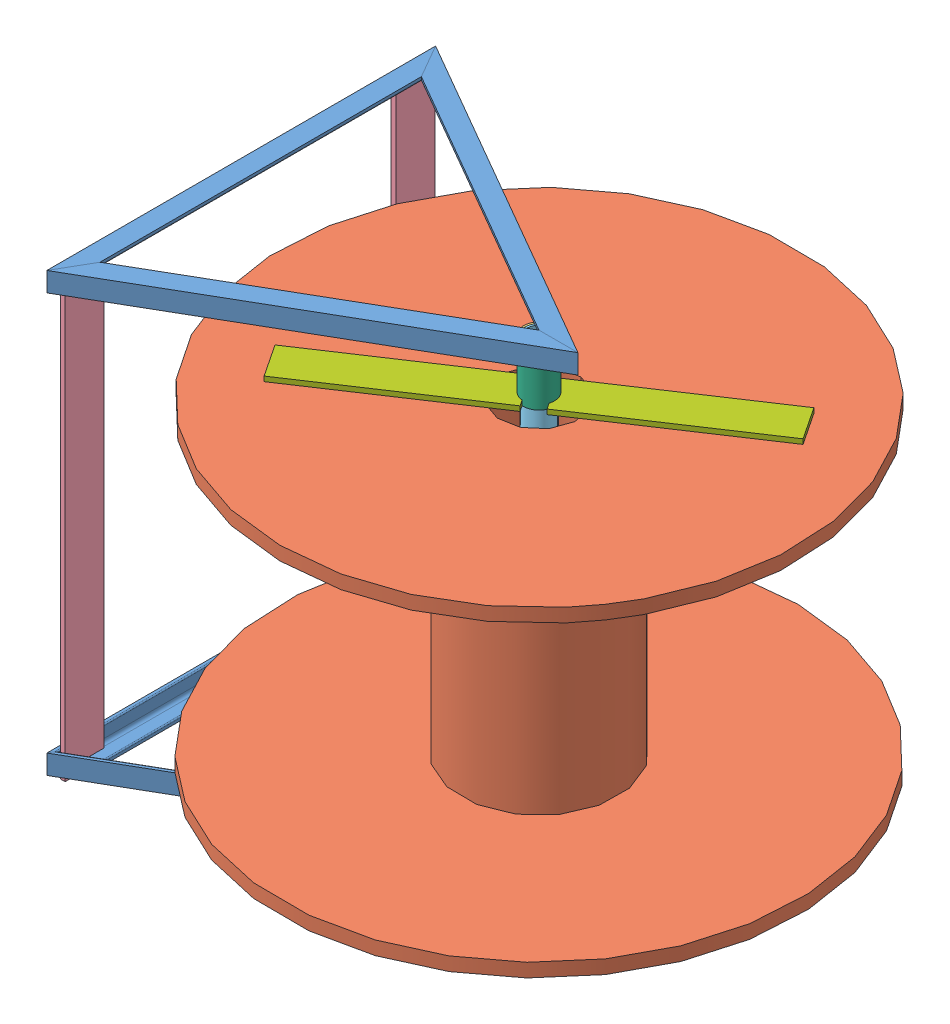
SolidWorks assembly Катушка для шланга, configuration По умолчанию. Lengths in mm.
Overall size (736.97 504 736.97).
22 component instances, 7 part files, 27 mates.
Components (placement in the parent):
- Ножка-1: Ножка [По умолчанию] at (-125.1048 -8.1589 -68.244) size (356.41 20 400)
  - Уголок-1: Уголок [По умолчанию] at (-73.7059 18.8462 -200.1369) size (20 20 400)
  - Уголок-2: Уголок [По умолчанию] at (-84.9559 18.8462 193.3679) x (-0.5 0 -0.866025) z (0.866025 0 -0.5) size (20 20 400)
  - Уголок-3: Уголок [По умолчанию] at (261.4543 18.8462 6.3583) x (-0.5 0 0.866025) z (-0.866025 0 -0.5) size (20 20 400)
- Ножка-2: Ножка [По умолчанию] at (-125.1048 464.5335 -68.5177) x (1 0 0) z (0 0 -1) size (356.41 20 400)
  - Уголок-1: Уголок [По умолчанию] at (-73.7059 18.8462 -200.1369) size (20 20 400)
  - Уголок-2: Уголок [По умолчанию] at (-84.9559 18.8462 193.3679) x (-0.5 0 -0.866025) z (0.866025 0 -0.5) size (20 20 400)
  - Уголок-3: Уголок [По умолчанию] at (261.4543 18.8462 6.3583) x (-0.5 0 0.866025) z (-0.866025 0 -0.5) size (20 20 400)
- Катушка-1: Катушка [По умолчанию] at (100.0995 379.1873 -68.3809) x (-0.824166 0 -0.566348) z (0 -1 0) size (530 530 330)
- Опора-1: Опора [По умолчанию] at (100.0995 433.1873 -68.3809) x (-0.837169 0 -0.546944) z (0 1 0) size (32 32 16)
- Опора-2: Опора [По умолчанию] at (100.0995 23.1873 -68.3809) x (-0.897984 0 -0.440028) z (0 -1 0) size (32 32 16)
- Перемычка-1: Перемычка [По умолчанию] at (-202.3106 449.1873 -258.5659) x (0 0 1) z (0 -1 0) size (40 5 452)
- Перемычка-2: Перемычка [По умолчанию] at (-202.3106 -2.8127 121.8042) x (0 0 -1) z (0 1 0) size (40 5 452)
- Вал-1: Вал [По умолчанию] at (100.0995 -50.8127 -68.3809) x (-0.495671 0 0.86851) z (0 1 0) size (28 28 500)
- Сборка - фланец-1: Сборка - фланец [По умолчанию] at (96.5514 25.4272 -65.404) x (-0.917606 0 0.397491) z (0 1 0) size (40 400 40)
  - Фланец-1: Фланец [По умолчанию] at (-4.4391 -1.3212 -2.24) size (32 32 40)
  - Деталь фланца-2: Деталь фланца [По умолчанию] at (15.5609 -201.3212 37.76) x (-1 0 0) z (0 1 0) size (40 5 190)
  - Деталь фланца-3: Деталь фланца [По умолчанию] at (-24.4391 198.6788 37.76) x (1 0 0) z (0 -1 0) size (40 5 190)
- Сборка - фланец-2: Сборка - фланец [По умолчанию] at (101.4552 430.9473 -63.9522) x (0.553322 0 0.832967) z (0 -1 0) size (40 400 40)
  - Фланец-1: Фланец [По умолчанию] at (-4.4391 -1.3212 -2.24) size (32 32 40)
  - Деталь фланца-2: Деталь фланца [По умолчанию] at (15.5609 -201.3212 37.76) x (-1 0 0) z (0 1 0) size (40 5 190)
  - Деталь фланца-3: Деталь фланца [По умолчанию] at (-24.4391 198.6788 37.76) x (1 0 0) z (0 -1 0) size (40 5 190)
Mates (geometry in assembly coordinates):
- Совпадение1: coincident anti-aligned: plane of Ножка-2/Уголок-3 through (-215.7106 449.1873 115.3379) normal (0 -1 0); plane of Опора-1 through (100.0995 449.1873 -68.3809) normal (0 1 0)
- Касательность1: tangent anti-aligned: plane of Ножка-2/Уголок-3 through (-208.3106 445.6873 128.155) normal (-0.5 0 -0.866025); cylinder of Опора-1 through (100.0995 449.1873 -68.3809) axis (0 -1 0) radius 16
- Касательность2: tangent anti-aligned: plane of Ножка-2/Уголок-2 through (138.0995 445.6873 -64.9168) normal (-0.5 0 0.866025); cylinder of Опора-1 through (100.0995 449.1873 -68.3809) axis (0 -1 0) radius 16
- Касательность3: tangent anti-aligned: plane of Ножка-1/Уголок-3 through (-208.3106 10.6873 -264.9168) normal (-0.5 0 0.866025); cylinder of Опора-2 through (100.0995 7.1873 -68.3809) axis (0 1 0) radius 16
- Совпадение2: coincident anti-aligned: plane of Ножка-1/Уголок-2 through (130.6995 7.1873 -84.6621) normal (0 1 0); plane of Опора-2 through (100.0995 7.1873 -68.3809) normal (0 -1 0)
- Касательность6: tangent anti-aligned: plane of Ножка-1/Уголок-2 through (138.0995 10.6873 -71.845) normal (-0.5 0 -0.866025); cylinder of Опора-2 through (100.0995 7.1873 -68.3809) axis (0 1 0) radius 16
- Параллельность1: parallel aligned: plane of Ножка-1/Уголок-2 through (140.0995 23.1873 -68.3809) normal (0.5 0 0.866025); plane of Ножка-2/Уголок-3 through (-206.3106 433.1873 131.6191) normal (0.5 0 0.866025)
- Совпадение6: coincident aligned: plane of Ножка-1/Уголок-1 through (-206.3106 23.1873 131.6191) normal (-1 0 0); plane of Ножка-2/Уголок-1 through (-206.3106 433.1873 -268.3809) normal (-1 0 0)
- Концентричный2: concentric anti-aligned: cylinder of Катушка-1 through (100.0995 63.1873 -68.3809) axis (0 1 0) radius 40; cylinder of Опора-1 through (100.0995 449.1873 -68.3809) axis (0 -1 0) radius 14
- Концентричный3: concentric aligned: cylinder of Катушка-1 through (100.0995 63.1873 -68.3809) axis (0 1 0) radius 40; cylinder of Опора-2 through (100.0995 7.1873 -68.3809) axis (0 1 0) radius 14
- Расстояние1: distance = 40 mm anti-aligned: plane of Катушка-1 through (100.0995 63.1873 -68.3809) normal (0 -1 0); plane of Опора-2 through (100.0995 23.1873 -68.3809) normal (0 1 0)
- Расстояние2: distance = 40 mm anti-aligned: plane of Катушка-1 through (100.0995 393.1873 -68.3809) normal (0 1 0); plane of Опора-1 through (100.0995 433.1873 -68.3809) normal (0 -1 0)
- Совпадение10: coincident anti-aligned: plane of Ножка-1/Уголок-1 through (-202.3106 10.6873 131.6191) normal (1 0 0); plane of Перемычка-1 through (-202.3106 -2.8127 -258.5659) normal (-1 0 0)
- Параллельность2: parallel anti-aligned: line of Ножка-1/Уголок-1 through (-202.3106 10.6873 124.6909) axis (0 0 -1); line of Перемычка-1 through (-197.3106 -2.8127 -258.5659) axis (0 0 1)
- Совпадение12: coincident anti-aligned: plane of Ножка-2/Уголок-1 through (-202.3106 445.6873 -268.3809) normal (1 0 0); plane of Перемычка-1 through (-202.3106 -2.8127 -258.5659) normal (-1 0 0)
- Совпадение13: coincident: plane of Ножка-1/Уголок-3 through (-208.3106 10.6873 -264.9168) normal (-0.5 0 0.866025); line of Перемычка-1 through (-197.3106 -2.8127 -258.5659) axis (0 1 0)
- Совпадение14: coincident: plane of Ножка-2/Уголок-1 through (-187.5106 449.1873 -268.3809) normal (0 -1 0); line of Перемычка-1 through (-197.3106 449.1873 -258.5659) axis (0 0 1)
- Совпадение15: coincident anti-aligned: plane of Ножка-2/Уголок-1 through (-202.3106 445.6873 -268.3809) normal (1 0 0); plane of Перемычка-2 through (-202.3106 449.1873 121.8042) normal (-1 0 0)
- Совпадение16: coincident anti-aligned: plane of Ножка-2/Уголок-1 through (-187.5106 449.1873 -268.3809) normal (0 -1 0); plane of Перемычка-2 through (-202.3106 449.1873 121.8042) normal (0 1 0)
- Совпадение17: coincident: plane of Ножка-2/Уголок-3 through (-208.3106 445.6873 128.155) normal (-0.5 0 -0.866025); line of Перемычка-2 through (-197.3106 449.1873 121.8042) axis (0 -1 0)
- Концентричный4: concentric anti-aligned: cylinder of Опора-2 through (100.0995 7.1873 -68.3809) axis (0 1 0) radius 14; cylinder of Вал-1 through (100.0995 449.1873 -68.3809) axis (0 -1 0) radius 14
- Концентричный5: concentric aligned: cylinder of Вал-1 through (100.0995 449.1873 -68.3809) axis (0 -1 0) radius 14; cylinder of Сборка - фланец-1/Фланец-1 through (100.0995 63.1873 -68.3809) axis (0 -1 0) radius 14
- Совпадение19: coincident anti-aligned: plane of Катушка-1 through (100.0995 393.1873 -68.3809) normal (0 1 0); plane of Сборка - фланец-2/Деталь фланца-3 through (89.0331 393.1873 -85.0402) normal (0 -1 0)
- Концентричный6: concentric anti-aligned: cylinder of Вал-1 through (100.0995 449.1873 -68.3809) axis (0 -1 0) radius 14; cylinder of Сборка - фланец-2/Фланец-1 through (100.0995 393.1873 -68.3809) axis (0 1 0) radius 14
- Совпадение20: coincident aligned: plane of ? through (177.8079 63.1873 -0.4674) normal (-0.44471 0 0.895675); plane of Сборка - фланец-2/Деталь фланца-2
- Совпадение21: coincident anti-aligned: plane of Катушка-1 through (100.0995 63.1873 -68.3809) normal (0 -1 0); plane of Сборка - фланец-1/Деталь фланца-3 through (118.4517 63.1873 -76.3307) normal (0 1 0)
- Совпадение22: coincident anti-aligned: circle of Опора-1; circle of Вал-1
